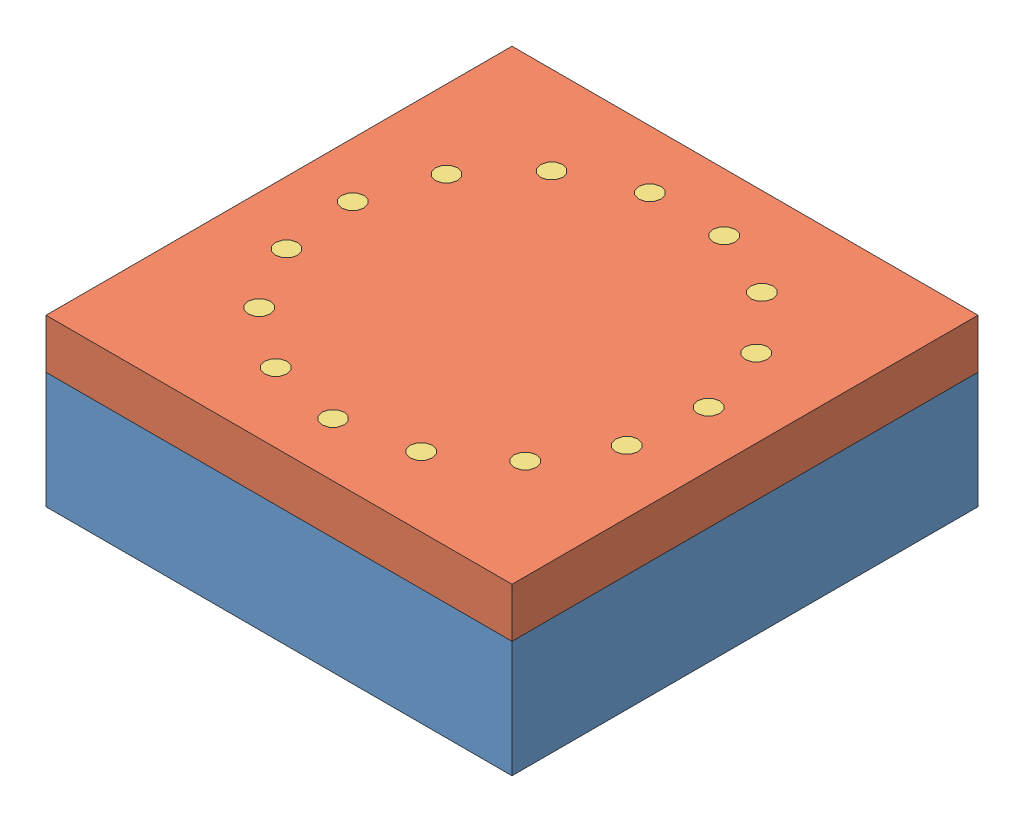
SolidWorks assembly Mold Assemv2, configuration Default. Lengths in mm.
Overall size (42 14.95 42).
3 component instances, 3 part files, 7 mates.
Components (placement in the parent):
- Cavityv2-1: Cavityv2 [Default] at origin size (42 12.5 42)
- Cavity No Cavityv2-1: Cavity No Cavityv2 [Default] at (0 13 0) x (-1 0 0) z (0 0 1) size (42 13.6 42)
- Mold Combinev2^Mold Assemv2-1: Mold Combinev2^Mold Assemv2 [Default] at (0 10.95 0) x (1 0 0) z (0 1 0) size (41.16 41.16 13.6) (hidden, virtual)
Mates (geometry in assembly coordinates):
- Coincident5: coincident aligned: plane of Cavityv2-1 through (21 6.5 21) normal (1 0 0); plane of Cavity No Cavityv2-1 through (21 6.5 21) normal (1 0 0)
- Coincident6: coincident aligned: plane of Cavityv2-1 through (21 6.5 -21) normal (0 0 -1); plane of Cavity No Cavityv2-1 through (-21 6.5 -21) normal (0 0 -1)
- InPlace1: in place: plane of Cavity No Cavityv2-1 through (0 10.95 0) normal (0 1 0); plane of Mold Combinev2^Mold Assemv2-1 through (0 10.95 0) normal (0 1 0); moOrthogonalPlaneRef_w of Cavity No Cavityv2-1 through (0 10.95 0) normal (0 1 0); plane of Mold Combinev2^Mold Assemv2-1 through (0 10.95 0) normal (0 0 -1); plane of Cavity No Cavityv2-1 through (0 10.95 0) normal (0 1 0); plane of Mold Combinev2^Mold Assemv2-1 through (0 10.95 0) normal (1 0 0); plane of Cavity No Cavityv2-1 through (0 10.95 0) normal (0 1 0); unknown of Mold Combinev2^Mold Assemv2-1
- Coincident7: coincident aligned: plane of Cavity No Cavityv2-1; plane of Mold Combinev2^Mold Assemv2-1
- Coincident8: coincident aligned: moOrthogonalPlaneRef_w of Cavity No Cavityv2-1 through (0 10.95 0) normal (0 0 -1); plane of Mold Combinev2^Mold Assemv2-1 through (0 10.95 0) normal (0 0 -1)
- Coincident9: coincident anti-aligned: moOrthogonalPlaneRef_w of Cavity No Cavityv2-1 through (0 10.95 0) normal (-1 0 0); plane of Mold Combinev2^Mold Assemv2-1 through (0 10.95 0) normal (1 0 0)
- Coincident10: coincident anti-aligned: plane of Cavityv2-1 through (0 6.5 0) normal (0 1 0); plane of Cavity No Cavityv2-1 through (0 6.5 0) normal (0 -1 0)
